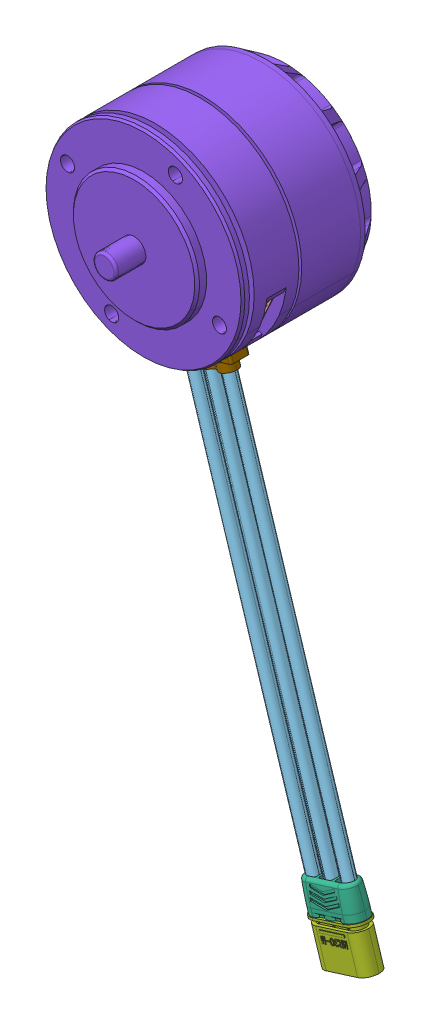
SolidWorks assembly M3508WithoutGear, configuration Default. Lengths in mm.
Overall size (70.45 147.45 43.4).
22 component instances, 11 part files, 0 mates.
Components (placement in the parent):
- 4_ASM^M3508WithoutGear-1: 4_ASM^M3508WithoutGear [Default] at (-1.7887 18.2683 39.841) x (-0.923508 0.383579 0) z (0.383579 0.923508 0) size (13.16 4.26 21.29) (virtual)
  - __-__10_1_^4_ASM_M3508WithoutGear-1: __-__10_1_^4_ASM_M3508WithoutGear [Default] at origin size (2.4 2.3 2.24) (virtual)
  - __-__10_3_^4_ASM_M3508WithoutGear-1: __-__10_3_^4_ASM_M3508WithoutGear [Default] at origin size (2.4 2.3 2.24) (virtual)
  - __-__10_2_^4_ASM_M3508WithoutGear-1: __-__10_2_^4_ASM_M3508WithoutGear [Default] at origin size (2.4 2.3 2.24) (virtual)
  - __-__20^4_ASM_M3508WithoutGear-1: __-__20^4_ASM_M3508WithoutGear [Default] at origin size (5.92 4.26 12.18) (virtual)
- 5_ASM^M3508WithoutGear-1: 5_ASM^M3508WithoutGear [Default] at (56.824 -105.7062 43.091) x (0.954008 0.299781 0) z (-0.299781 0.954008 0) size (12.31 5.48 111.01) (virtual)
  - 15^5_ASM_M3508WithoutGear-1: 15^5_ASM_M3508WithoutGear [Default] at (-14.7519 0 22.9937) x (-1 0 0) z (0 0 -1) size (2.5 2.5 100) (virtual)
  - 15^5_ASM_M3508WithoutGear-2: 15^5_ASM_M3508WithoutGear [Default] at (-18.7519 0 22.9937) x (0 1 0) z (0 0 -1) size (2.5 2.5 100) (virtual)
  - 15^5_ASM_M3508WithoutGear-3: 15^5_ASM_M3508WithoutGear [Default] at (-22.7519 0 22.9937) x (-1 0 0) z (0 0 -1) size (2.5 2.5 100) (virtual)
  - 20^5_ASM_M3508WithoutGear-1: 20^5_ASM_M3508WithoutGear [Default] at (-1.9783 -5.4851 11.3276) x (1 0 0) z (0 0 -1) size (11.94 4.93 6.5) (virtual)
  - 19^5_ASM_M3508WithoutGear-1: 19^5_ASM_M3508WithoutGear [Default] at origin size (12.31 5.48 13.41) (virtual)
- 2_ASM^M3508WithoutGear-1: 2_ASM^M3508WithoutGear [Default] at (-1.7887 18.2683 50.441) x (-0.378508 0.925598 0) z (0.925598 0.378508 0) (virtual)
  - 26_ASM^2_ASM_M3508WithoutGear-1: 26_ASM^2_ASM_M3508WithoutGear [Default] at (0 34.5 0) x (-0.381788 0 0.92425) z (-0.92425 0 -0.381788) (virtual)
    - 28^26_ASM_2_ASM_M3508WithoutGear-1: 28^26_ASM_2_ASM_M3508WithoutGear [Default] at (0 2.5 0) (suppressed, hidden, virtual)
    - 27^26_ASM_2_ASM_M3508WithoutGear-1: 27^26_ASM_2_ASM_M3508WithoutGear [Default] at origin (suppressed, hidden, virtual)
    - 28^26_ASM_2_ASM_M3508WithoutGear-2: 28^26_ASM_2_ASM_M3508WithoutGear [Default] at (0 -2.7 0) (suppressed, hidden, virtual)
  - 26_ASM^2_ASM_M3508WithoutGear-2: 26_ASM^2_ASM_M3508WithoutGear [Default] at (0 27 0) x (-0.381788 0 0.92425) z (-0.92425 0 -0.381788) (virtual)
    - 28^26_ASM_2_ASM_M3508WithoutGear-1: 28^26_ASM_2_ASM_M3508WithoutGear [Default] at (0 2.5 0) (suppressed, hidden, virtual)
    - 27^26_ASM_2_ASM_M3508WithoutGear-1: 27^26_ASM_2_ASM_M3508WithoutGear [Default] at origin (suppressed, hidden, virtual)
    - 28^26_ASM_2_ASM_M3508WithoutGear-2: 28^26_ASM_2_ASM_M3508WithoutGear [Default] at (0 -2.7 0) (suppressed, hidden, virtual)
- 1_1^M3508WithoutGear-1: 1_1^M3508WithoutGear [Default] at (-1.7887 18.2683 48.441) x (0.923508 -0.383579 0) z (0 0 1) size (42 42 43.4) (virtual)
- 3^M3508WithoutGear-1: 3^M3508WithoutGear [Default] at (4.5067 -1.7659 43.091) x (0.299781 -0.954008 0) z (0.954008 0.299781 0) size (5.77 4 14.5) (virtual)
